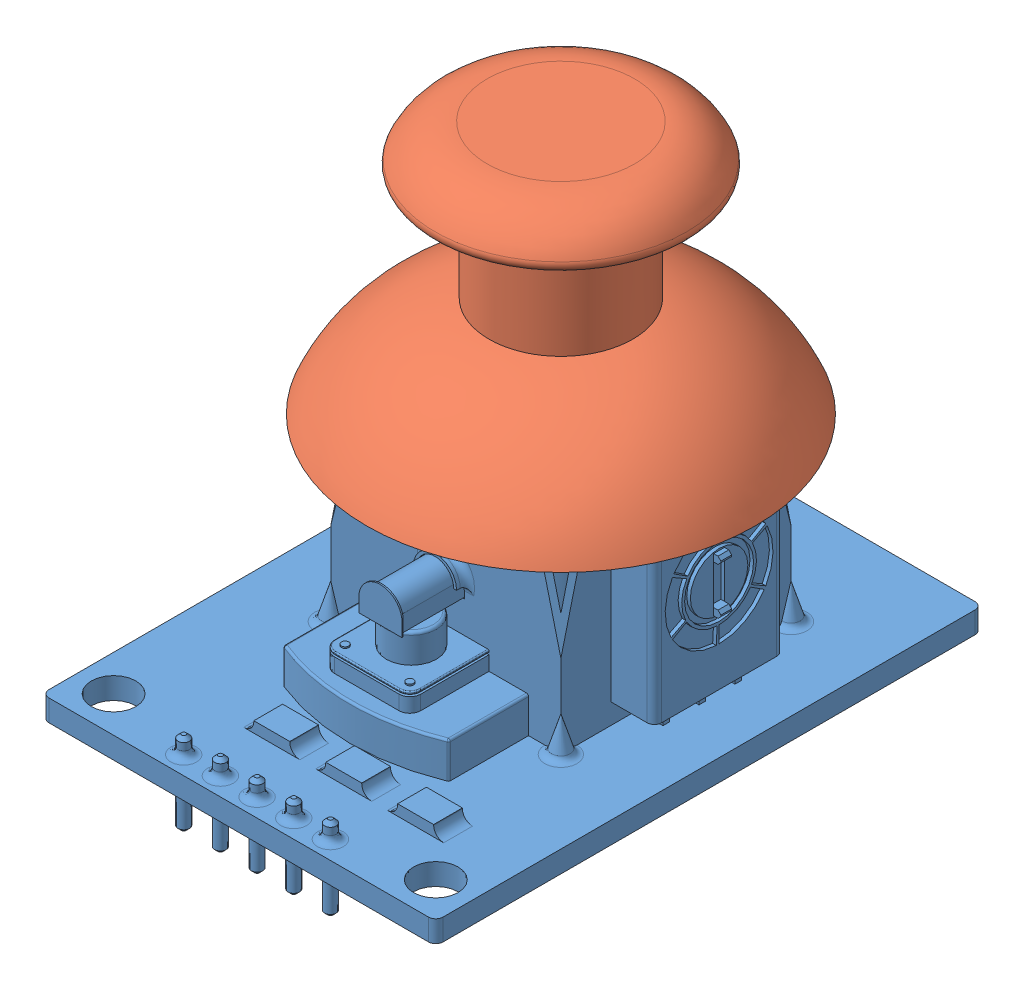
SolidWorks assembly Joystick, configuration Default. Lengths in mm.
Overall size (27.4 34.62 38).
2 component instances, 2 part files, 8 mates.
Components (placement in the parent):
- Joystick Breakout Mod-1: Joystick Breakout Mod [Default] at (14.9094 17.5433 30.3396) size (27.4 25.5 38)
- Joystick Sample Cap-1: Joystick Sample Cap [Default] at (14.9094 17.5433 26.9396) size (27 17.62 27)
Mates (geometry in assembly coordinates):
- InPlace1: in place: plane of Joystick Breakout Mod-1 through (14.9094 40.0433 30.3396) normal (0 1 0); plane of ? through (0 40.0433 0) normal (0 1 0); moOrthogonalPlaneRef_w of Joystick Breakout Mod-1 through (14.9094 40.0433 30.3396) normal (0 1 0); plane of ? through (0 40.0433 0) normal (0 0 -1); plane of Joystick Breakout Mod-1 through (14.9094 40.0433 30.3396) normal (0 1 0); plane of ? through (0 40.0433 0) normal (1 0 0); plane of Joystick Breakout Mod-1 through (14.9094 40.0433 30.3396) normal (0 1 0); unknown of ?
- Coincident1: coincident: plane of Joystick Breakout Mod-1; plane of ?
- Coincident2: coincident: moOrthogonalPlaneRef_w of Joystick Breakout Mod-1 through (14.9094 40.0433 30.3396) normal (0 0 -1); plane of ? through (14.9094 40.0433 30.3396) normal (0 0 -1)
- Coincident3: coincident: moOrthogonalPlaneRef_w of Joystick Breakout Mod-1 through (14.9094 40.0433 30.3396) normal (-1 0 0); plane of ? through (14.9094 40.0433 30.3396) normal (1 0 0)
- InPlace2: in place: plane of Joystick Breakout Mod-1 through (14.9094 17.5433 26.9396) normal (0 0 1); plane of Joystick Sample Cap-1 through (14.9094 17.5433 26.9396) normal (0 0 1); plane of Joystick Breakout Mod-1 through (14.9094 17.5433 26.9396) normal (0 0 1); plane of Joystick Sample Cap-1 through (14.9094 17.5433 26.9396) normal (0 1 0); plane of Joystick Breakout Mod-1 through (14.9094 17.5433 26.9396) normal (0 0 1); plane of Joystick Sample Cap-1 through (14.9094 17.5433 26.9396) normal (1 0 0); plane of Joystick Breakout Mod-1 through (14.9094 17.5433 26.9396) normal (0 0 1); unknown of Joystick Sample Cap-1
- Coincident4: coincident: plane of Joystick Breakout Mod-1; plane of Joystick Sample Cap-1
- Coincident5: coincident: moOrthogonalPlaneRef_w of Joystick Breakout Mod-1 through (14.9094 17.5433 26.9396) axis (0 1 0); plane of Joystick Sample Cap-1 through (14.9094 17.5433 26.9396) normal (0 1 0)
- Coincident6: coincident: moOrthogonalPlaneRef_w of Joystick Breakout Mod-1 through (14.9094 17.5433 26.9396) axis (-1 0 0); plane of Joystick Sample Cap-1 through (14.9094 17.5433 26.9396) normal (1 0 0)
